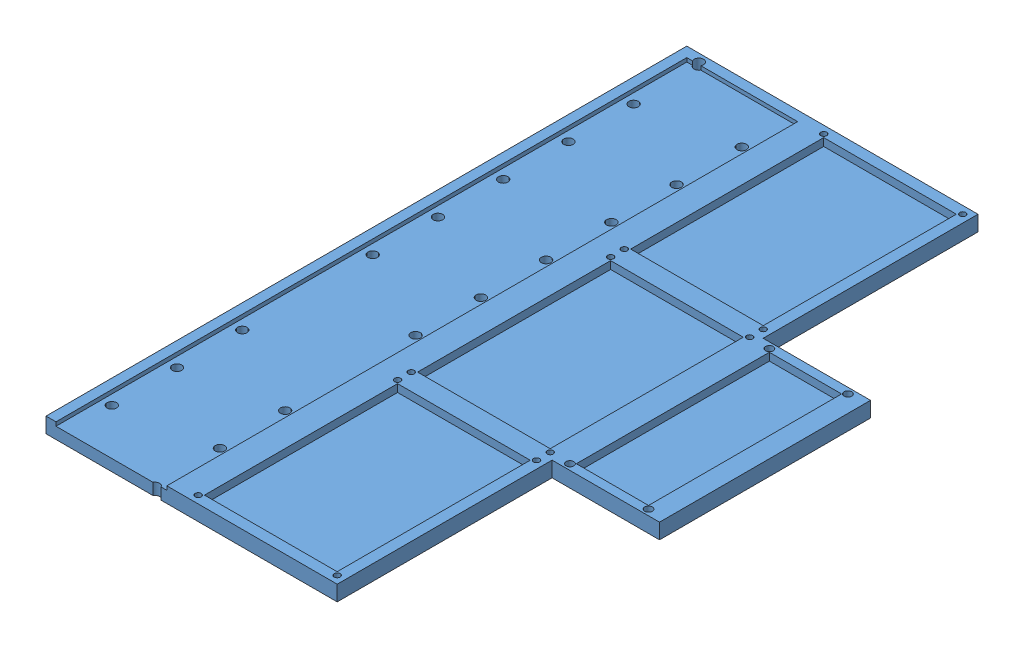
SolidWorks assembly Driver_power_housing, configuration Default. Lengths in mm.
Overall size (131.94 5.08 212.09).
15 component instances, 4 part files, 17 mates.
Components (placement in the parent):
- pcb3x7-1: pcb3x7 [Default] at (-73.0022 7.874 -102.1286) x (0 0 -1) z (-1 0 0) size (70 1.52 30) (hidden)
- Carte proto 7x5.stp-1: Carte proto 7x5.stp [Default] at (-114.2326 7.85 -178.1987) x (0 0 1) z (0 -1 0) size (70 50 1.55) (hidden)
- DC-DC XL6009E1-2: DC-DC XL6009E1 [По умолчанию] at (-163.4226 6.35 -203.1712) size (43.3 13.75 21.1) (hidden)
- DC-DC XL6009E1-3: DC-DC XL6009E1 [По умолчанию] at (-163.4226 6.35 -181.5812) size (43.3 13.75 21.1) (hidden)
- DC-DC XL6009E1-4: DC-DC XL6009E1 [По умолчанию] at (-163.4226 6.35 -159.9912) size (43.3 13.75 21.1) (hidden)
- DC-DC XL6009E1-5: DC-DC XL6009E1 [По умолчанию] at (-163.4226 6.35 -138.4012) size (43.3 13.75 21.1) (hidden)
- DC-DC XL6009E1-6: DC-DC XL6009E1 [По умолчанию] at (-163.4226 6.35 -116.8112) size (43.3 13.75 21.1) (hidden)
- DC-DC XL6009E1-7: DC-DC XL6009E1 [По умолчанию] at (-163.4226 6.35 -95.2212) size (43.3 13.75 21.1) (hidden)
- DC-DC XL6009E1-8: DC-DC XL6009E1 [По умолчанию] at (-163.4226 6.35 -73.6312) size (43.3 13.75 21.1) (hidden)
- DC-DC XL6009E1-9: DC-DC XL6009E1 [По умолчанию] at (-163.4226 6.35 -52.0412) size (43.3 13.75 21.1) (hidden)
- DC-DC XL6009E1-10: DC-DC XL6009E1 [По умолчанию] at (-163.4226 6.35 -30.4512) size (43.3 13.75 21.1) (hidden)
- DC-DC XL6009E1-11: DC-DC XL6009E1 [По умолчанию] at (-163.4226 6.35 -8.8612) size (43.3 13.75 21.1) (hidden)
- Part4^Driver_power_housing-1: Part4^Driver_power_housing [Default] at origin size (131.94 5.08 212.09) (virtual)
- Carte proto 7x5.stp-2: Carte proto 7x5.stp [Default] at (-114.2326 7.85 -37.1537) x (0 0 -1) z (0 -1 0) size (70 50 1.55) (hidden)
- Carte proto 7x5.stp-3: Carte proto 7x5.stp [Default] at (-114.2326 7.85 -107.6762) x (0 0 -1) z (0 -1 0) size (70 50 1.55) (hidden)
Mates (geometry in assembly coordinates):
- Coincident11: coincident: plane of DC-DC XL6009E1-2 through (-185.0726 7.95 -192.6212) normal (-1 0 0); plane of Part4^Driver_power_housing-1 through (-185.0726 6.35 -1.6312) normal (-1 0 0)
- Coincident12: coincident: plane of DC-DC XL6009E1-2 through (-163.4226 6.35 -203.1712) normal (0 -1 0); plane of Part4^Driver_power_housing-1 through (0 6.35 0) normal (0 1 0)
- Coincident30: coincident: plane of DC-DC XL6009E1-2 through (-185.0726 7.95 -213.7212) normal (0 0 -1); plane of Part4^Driver_power_housing-1 through (-88.6883 6.35 -213.7212) normal (0 0 -1)
- Coincident14: coincident: plane of pcb3x7-1 through (-73.0022 6.35 -102.1286) normal (0 -1 0); plane of Part4^Driver_power_housing-1 through (0 6.35 0) normal (0 1 0)
- Parallel2: parallel: plane of pcb3x7-1 through (-86.6926 6.35 -72.6762) normal (-1 0 0); plane of DC-DC XL6009E1-2 through (-141.7726 7.95 -192.6212) normal (1 0 0)
- Distance3: distance = 2.54 mm: plane of pcb3x7-1 through (-86.6926 6.35 -72.6762) normal (-1 0 0); plane of Carte proto 7x5.stp-3 through (-89.2326 7.85 -72.6762) normal (1 0 0)
- Coincident17: coincident: plane of Carte proto 7x5.stp-1 through (-114.2326 6.35 -178.1987) normal (0 -1 0); plane of Part4^Driver_power_housing-1 through (0 6.35 0) normal (0 1 0)
- Width1: width: plane of pcb3x7-1 through (-56.6926 6.35 -142.6762) normal (0 0 -1); plane of pcb3x7-1 through (-56.6926 6.35 -72.6762) normal (0 0 1); plane of Part4^Driver_power_housing-1 through (-88.6883 6.35 -1.6312) normal (0 0 1); plane of Part4^Driver_power_housing-1 through (-88.6883 6.35 -213.7212) normal (0 0 -1)
- Coincident201: coincident: plane of Part4^Driver_power_housing-1 through (0 6.35 0) normal (0 1 0); line of Carte proto 7x5.stp-2 through (-89.2326 6.35 -72.1537) axis (0 0 1)
- Width4: width: plane of Carte proto 7x5.stp-3 through (-89.2326 7.85 -142.6762) normal (0 0 -1); plane of Carte proto 7x5.stp-3 through (-139.2326 7.85 -72.6762) normal (0 0 1); plane of Part4^Driver_power_housing-1 through (-88.6883 6.35 -1.6312) normal (0 0 1); plane of Part4^Driver_power_housing-1 through (-88.6883 6.35 -213.7212) normal (0 0 -1)
- Coincident24: coincident: plane of Part4^Driver_power_housing-1 through (0 6.35 0) normal (0 1 0); plane of Carte proto 7x5.stp-3 through (-114.2326 6.35 -107.6762) normal (0 -1 0)
- Distance6: distance = 2.54 mm: plane of Carte proto 7x5.stp-3 through (-139.2326 7.85 -142.6762) normal (-1 0 0); plane of DC-DC XL6009E1-2 through (-141.7726 7.95 -192.6212) normal (1 0 0)
- Coincident29: coincident: plane of Carte proto 7x5.stp-1 through (-139.2326 7.85 -213.1987) normal (-1 0 0); plane of Carte proto 7x5.stp-3 through (-139.2326 7.85 -142.6762) normal (-1 0 0)
- Width6: width: plane of Carte proto 7x5.stp-1 through (-139.2326 7.85 -143.1987) normal (0 0 1); plane of Carte proto 7x5.stp-1 through (-89.2326 7.85 -213.1987) normal (0 0 -1); plane of Part4^Driver_power_housing-1 through (-88.6883 6.35 -213.7212) normal (0 0 -1); plane of Carte proto 7x5.stp-3 through (-89.2326 7.85 -142.6762) normal (0 0 -1)
- Width7: width: plane of Carte proto 7x5.stp-2 through (-89.2326 7.85 -72.1537) normal (0 0 -1); plane of Carte proto 7x5.stp-2 through (-139.2326 7.85 -2.1537) normal (0 0 1); plane of Part4^Driver_power_housing-1 through (-88.6883 6.35 -1.6312) normal (0 0 1); plane of Carte proto 7x5.stp-3 through (-139.2326 7.85 -72.6762) normal (0 0 1)
- Coincident32: coincident: plane of Part4^Driver_power_housing-1 through (0 6.35 0) normal (0 1 0); plane of Carte proto 7x5.stp-2 through (-114.2326 6.35 -37.1537) normal (0 -1 0)
- Coincident33: coincident: plane of Carte proto 7x5.stp-2 through (-139.2326 7.85 -72.1537) normal (-1 0 0); plane of Carte proto 7x5.stp-3 through (-139.2326 7.85 -142.6762) normal (-1 0 0)
